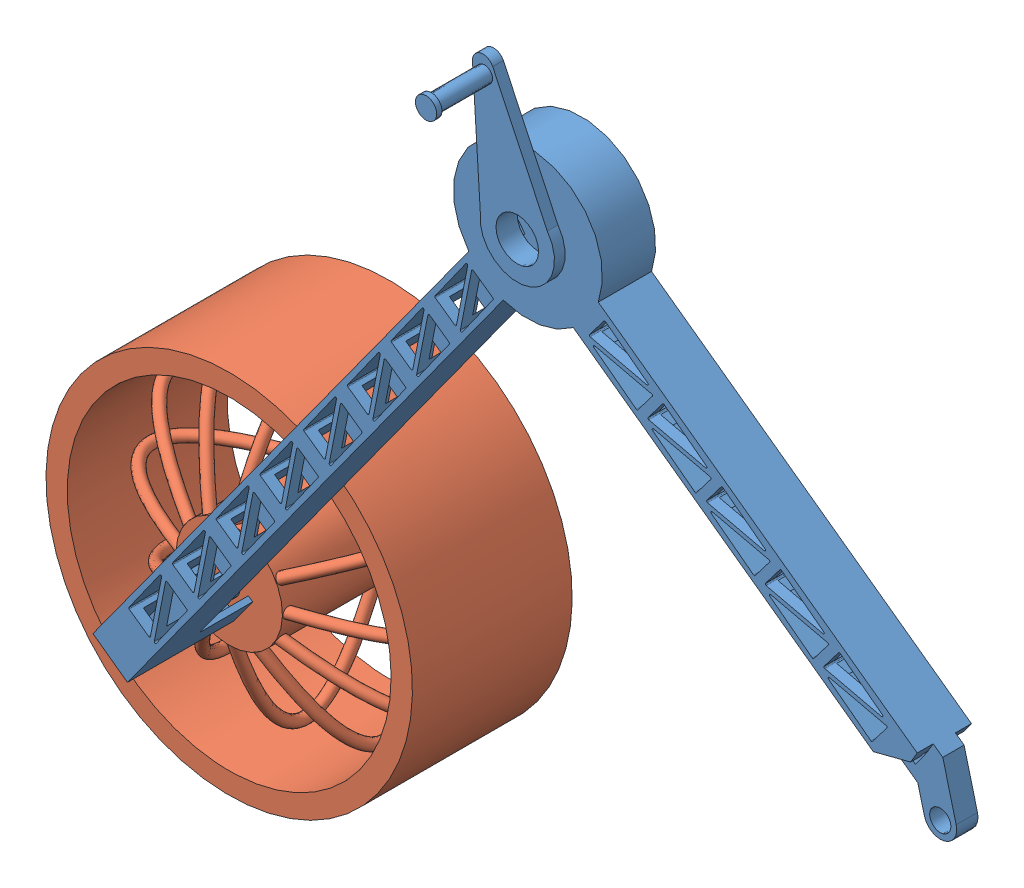
SolidWorks assembly mirrorassem, configuration Default. Lengths in mm.
Overall size (958.31 910.95 315).
2 component instances, 2 part files, 2 mates.
Components (placement in the parent):
- UPPERROCKERmirror-1: UPPERROCKERmirror [Default] at (327.7742 187.4834 756.9095) x (0.968136 0.250423 0) z (0 0 1) size (828.95 580.17 215)
- ROVERRIM-1: ROVERRIM [Default] at (-139.7155 76.4336 526.9095) x (-0.02313 -0.999732 0) z (0 0 -1) size (344.1 344.1 150)
Mates (geometry in assembly coordinates):
- Concentric6: concentric aligned: cylinder of UPPERROCKERmirror-1 through (-139.7155 76.4336 476.9095) axis (0 0 1) radius 10; cylinder of ROVERRIM-1 through (-139.7155 76.4336 426.9095) axis (0 0 1) radius 10
- Coincident9: coincident anti-aligned: plane of UPPERROCKERmirror-1 through (327.7742 187.4834 526.9095) normal (0 0 -1); plane of ROVERRIM-1 through (-139.7155 76.4336 526.9095) normal (0 0 1)
